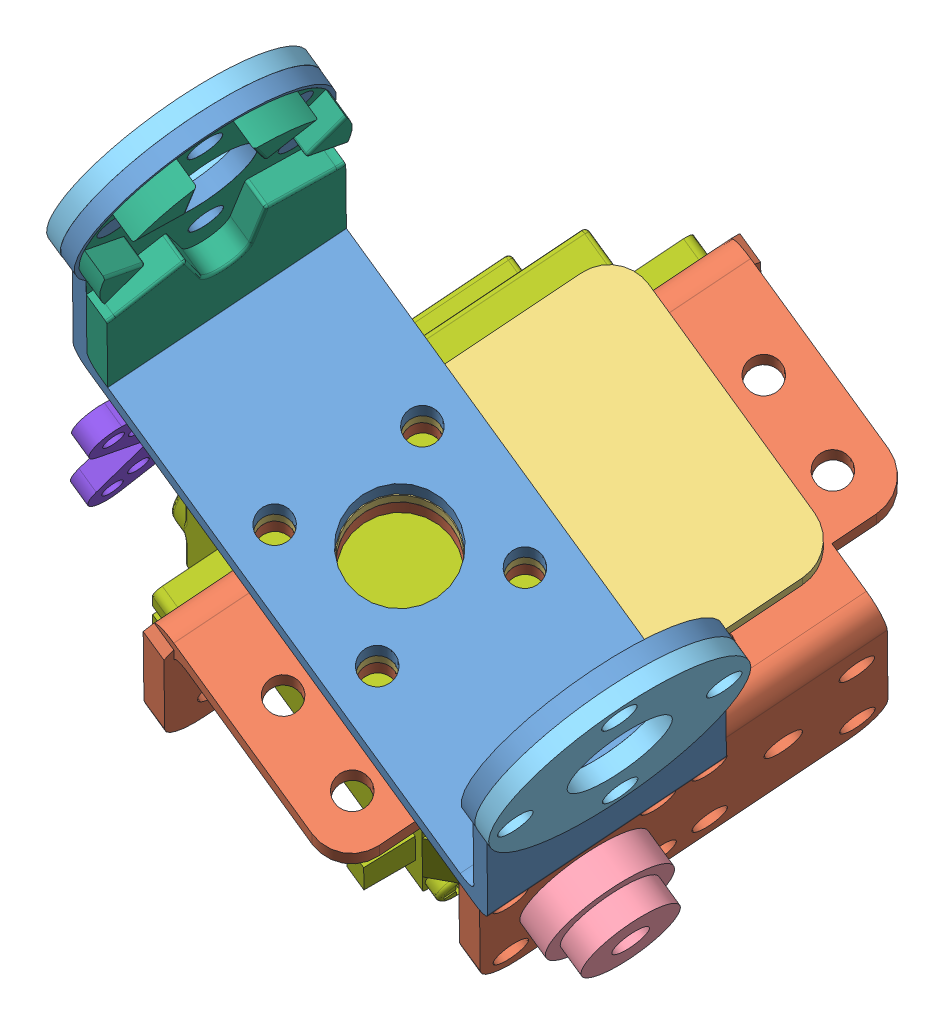
SolidWorks assembly box2_right_bushing_servo, configuration Predeterminado. Lengths in mm.
Overall size (104.88 113.33 91.02).
11 component instances, 8 part files, 5 mates.
Components (placement in the parent):
- box2_right_bushing-1: box2_right_bushing [Predeterminado] at (-19.6174 -19.058 -72.8548) x (0.860754 -0.506151 0.053973) z (-0.272355 -0.368377 0.888888) size (65.67 74.14 60.47)
  - box2_right-1: box2_right [Predeterminado] at (2.9022 60.2896 -29.0999) size (60 74.14 60.47)
    - u_bracket-1: u_bracket [Predeterminado] at (-18.6428 -64.1261 18.1896) x (1 0 0) z (0 0.017646 0.999844) size (60 44.22 26.36)
    - multi_purpose_bracket-3: multi_purpose_bracket [Predeterminado] at (-6.4228 -67.2977 8.4941) x (0 -0.017646 -0.999844) z (-1 0 0) size (60 27 38.5)
    - box1_supplement-1: box1_supplement [Predeterminado] at (-14.1428 -67.2944 8.679) x (1 0 0) z (0 0.017646 0.999844) size (32 2 41.37)
  - bushing-1: bushing [Predeterminado] at (13.7294 -22.6991 -10.3274) x (0 -1 0) z (0 0 1) size (13 6.7 13)
  - suplement_external_bracket-1: suplement_external_bracket [Predeterminado] at (-47.7406 26.1989 -11.4404) x (0 0.017646 0.999844) z (0 0.999844 -0.017646) size (26.36 2 26.36)
  - supplement_u_f_horn-1: supplement_u_f_horn [Predeterminado] at (-43.7406 26.1989 -11.4404) x (0 0.999844 -0.017646) z (0 -0.017646 -0.999844) size (40.74 3.02 25.4)
  - suplement_external_bracket-2: suplement_external_bracket [Predeterminado] at (14.2594 26.1989 -11.4404) x (0 -0.999844 0.017646) z (0 0.017646 0.999844) size (26.36 2 26.36)
- mg946R-1: mg946R [Predeterminado] at (-19.7949 -31.732 -101.2531) x (0.434768 0.786193 0.439178) z (-0.264724 -0.354559 0.896777) size (20.1 44.9 54.4)
- start_horn-1: start_horn [Predeterminado] at (-63.2948 -11.3569 -94.6643) x (-0.259635 -0.345365 0.901839) z (0.437826 0.790275 0.428688) size (28.38 5.5 32)
Mates (geometry in assembly coordinates):
- Coincidente8: coincident anti-aligned: plane of mg946R-1 through (-61.1429 -12.6223 -94.5294) normal (-0.860754 0.506151 -0.053973); plane of start_horn-1 through (-55.2323 -1.9536 -88.7421) normal (0.860754 -0.506151 0.053973)
- Concéntrica7: concentric aligned: circle of mg946R-1; circle of start_horn-1
- Concéntrica8: concentric aligned: cylinder of mg946R-1 through (-61.1429 -12.6223 -94.5294) axis (0.860754 -0.506151 0.053973) radius 3; cylinder of box2_right_bushing-1/box2_right-1/multi_purpose_bracket-3 through (-50.0401 -19.1512 -93.8332) axis (0.860754 -0.506151 0.053973) radius 1.95
- Paralelo1: parallel anti-aligned: plane of mg946R-1 through (-34.5963 -2.2256 -116.5374) normal (0.434768 0.786193 0.439178); plane of box2_right_bushing-1/box2_right-1/multi_purpose_bracket-3 through (-21.3536 -17.5089 -95.8668) normal (-0.434768 -0.786193 -0.439178)
- Coincidente9: coincident anti-aligned: plane of box2_right_bushing-1/box2_right-1/multi_purpose_bracket-3 through (-41.5413 -15.8457 -133.5066) normal (-0.860754 0.506151 -0.053973); plane of mg946R-1 through (-44.3264 -17.3067 -102.7914) normal (0.860754 -0.506151 0.053973)
